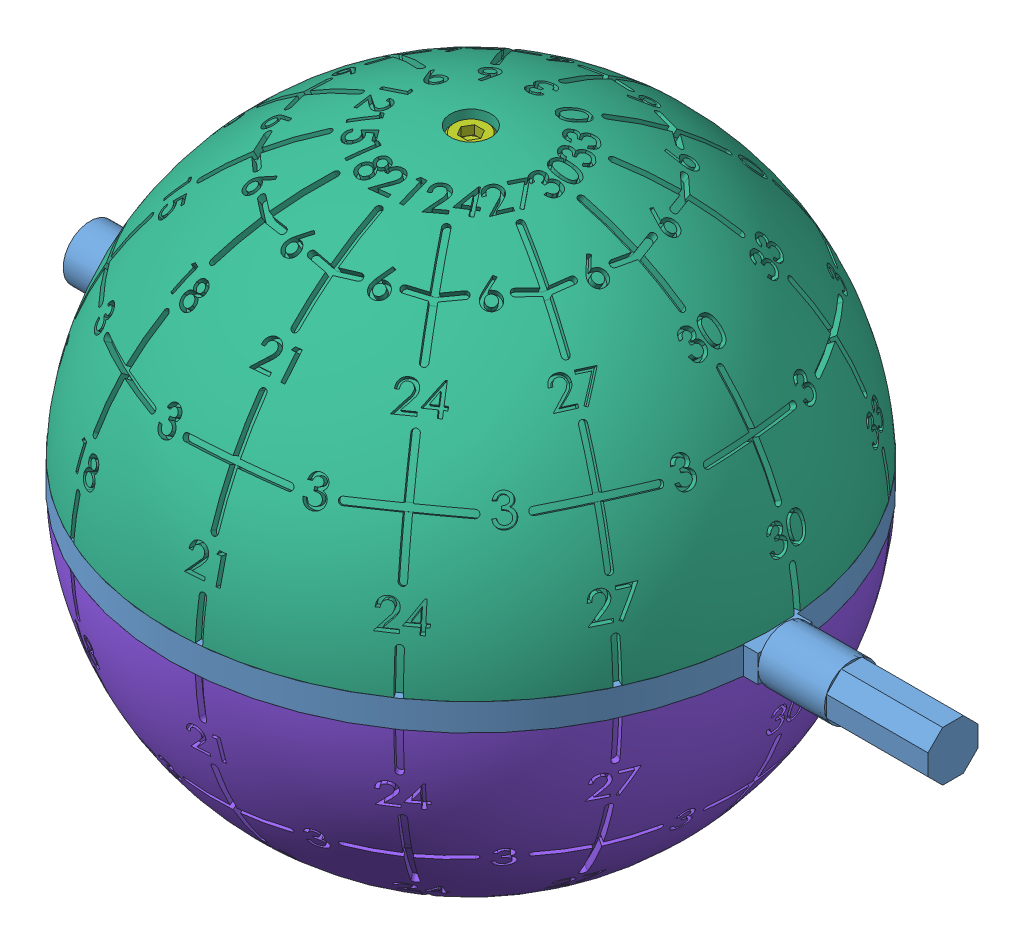
SolidWorks assembly Yaw, configuration Default. Lengths in mm.
Overall size (130.2 88.9 117.86).
9 component instances, 8 part files, 20 mates.
Components (placement in the parent):
- BallPlate-1: BallPlate [Default] at (53.019 65.1893 92.0131) size (127.54 8 88.9)
- SKF 625-1: SKF 625 [Default] at (53.019 62.6893 92.0131) x (0 1 0) z (-0.440998 0 0.897508) size (5 16 16)
- Servo-1: Servo [noHorn] at (53.019 67.1893 71.9881) x (0 0 -1) z (1 0 0) size (19.8 47.23 67)
- YawServoGear-1: YawServoGear [Default] at (42.719 84.6893 71.9881) x (-0.590306 0 0.80718) z (0 -1 0) size (24.43 24.43 4)
- BallShaft_V2-1: BallShaft_V2 [Default] at (53.019 65.1893 92.0131) x (-0.986105 0 0.166123) z (-0.166123 0 -0.986105) size (24.43 75.9 24.43)
- Ball_V9.1_Top-1: Ball_V9.1_Top [Default] at (53.019 65.1893 92.0131) x (-0.907868 0 -0.419257) z (0.419257 0 -0.907868) size (88.8 42.45 88.81)
- socket head cap screw_am-1: socket head cap screw_am [B18.3.1M - 3 x 0.5 x 20 Hex SHCS -- 20SHX] at (53.019 108.6393 92.0131) x (0 -1 0) z (0 0 1) size (23 5.5 5.5)
- Ball_V9.1_Bot-1: Ball_V9.1_Bot [Default] at (53.019 65.1893 92.0131) x (-0.907868 0 -0.419257) z (0.419257 0 -0.907868) size (88.8 87.56 88.81)
- socket head cap screw_am-2: socket head cap screw_am [B18.3.1M - 3 x 0.5 x 20 Hex SHCS -- 20SHX] at (53.019 21.7393 92.0131) x (0 1 0) z (0.546944 0 -0.837169) size (23 5.5 5.5)
Mates (geometry in assembly coordinates):
- Width1: width: plane of BallPlate-1 through (53.019 67.6893 92.0131) normal (0 1 0); plane of BallPlate-1 through (53.019 62.6893 92.0131) normal (0 1 0); plane of SKF 625-1 through (49.3392 62.6893 90.205) normal (0 -1 0); plane of SKF 625-1 through (50.506 67.6893 90.7783) normal (0 1 0)
- Concentric1: concentric: circle of BallPlate-1; circle of SKF 625-1
- Width2: width: plane of BallPlate-1 through (32.313 76.3693 61.8901) normal (0 0 1); plane of BallPlate-1 through (32.313 76.3693 82.0861) normal (0 0 -1); plane of Servo-1 through (32.719 67.1893 62.0881) normal (0 0 -1); plane of Servo-1 through (32.719 67.1893 81.8881) normal (0 0 1)
- Width3: width: plane of BallPlate-1 through (73.725 67.1893 82.0861) normal (-1 0 0); plane of BallPlate-1 through (32.313 67.1893 82.0861) normal (1 0 0); plane of Servo-1 through (73.319 67.1893 81.8881) normal (1 0 0); plane of Servo-1 through (32.719 67.1893 81.8881) normal (-1 0 0)
- Coincident1: coincident: plane of BallPlate-1 through (53.019 67.1893 92.0131) normal (0 1 0); plane of Servo-1 through (53.019 67.1893 71.9881) normal (0 -1 0)
- Concentric2: concentric: circle of Servo-1; circle of YawServoGear-1
- Coincident2: coincident: plane of Servo-1 through (42.719 84.6893 71.9881) normal (0 1 0); plane of YawServoGear-1 through (42.719 84.6893 71.9881) normal (0 1 0)
- Concentric3: concentric: cylinder of BallPlate-1 through (53.019 67.6893 92.0131) axis (0 -1 0) radius 10.125; circle of BallShaft_V2-1
- Coincident3: coincident: plane of BallPlate-1 through (53.019 67.6893 92.0131) normal (0 1 0); plane of BallShaft_V2-1 through (53.019 67.6893 92.0131) normal (0 -1 0)
- GearMate2: gear = 1 : 1 mm: cylinder of BallShaft_V2-1 through (53.019 79.6893 92.0131) axis (0 -1 0) radius 4; cylinder of YawServoGear-1 through (42.719 84.6893 71.9881) axis (0 -1 0) radius 2.9
- Concentric4: concentric: circle of BallPlate-1; circle of Ball_V9.1_Top-1
- Coincident4: coincident: plane of BallPlate-1 through (53.019 67.1893 92.0131) normal (0 1 0); plane of Ball_V9.1_Top-1 through (53.019 67.1893 92.0131) normal (0 -1 0)
- GearMate3: gear = 3.1 : 4.2 mm: cylinder of BallShaft_V2-1 through (53.019 63.3052 92.0131) axis (0 1 0) radius 1.55; cylinder of Ball_V9.1_Top-1 through (53.019 101.6393 92.0131) axis (0 1 0) radius 1.55
- Concentric5: concentric: circle of Ball_V9.1_Top-1; circle of socket head cap screw_am-1
- Coincident5: coincident: plane of Ball_V9.1_Top-1 through (53.019 105.6393 92.0131) normal (0 1 0); plane of socket head cap screw_am-1 through (55.769 105.6393 92.0131) normal (0 -1 0)
- Coincident6: coincident: plane of BallPlate-1 through (53.019 63.1893 92.0131) normal (0 -1 0); plane of Ball_V9.1_Bot-1 through (53.019 63.1893 92.0131) normal (0 1 0)
- Concentric6: concentric: circle of BallPlate-1; circle of Ball_V9.1_Bot-1
- Coincident7: coincident: plane of Ball_V9.1_Top-1 through (71.655 65.1893 51.6583) normal (0.419257 0 -0.907868); plane of Ball_V9.1_Bot-1 through (71.655 65.1893 51.6583) normal (0.419257 0 -0.907868)
- Concentric8: concentric: circle of Ball_V9.1_Bot-1; circle of socket head cap screw_am-2
- Coincident8: coincident: plane of Ball_V9.1_Bot-1 through (53.019 24.7393 92.0131) normal (0 -1 0); plane of socket head cap screw_am-2 through (55.3212 24.7393 93.5172) normal (0 1 0)
